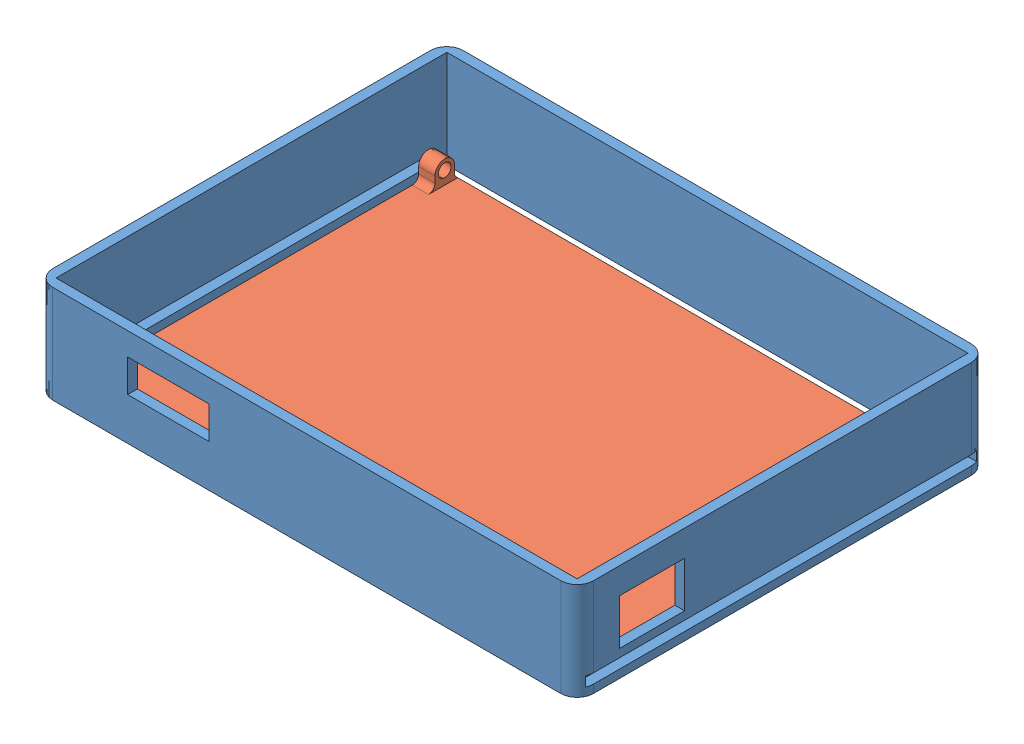
SolidWorks assembly 装配体1, configuration 默认. Lengths in mm.
Overall size (166 32 126).
2 component instances, 2 part files, 2 mates.
Components (placement in the parent):
- 外框-1: 外框 [默认] at (-89.7958 -29.2658 166) size (166 30 126)
- 后盖-1: 后盖 [默认] at (-90.2958 -31.2658 165.6592) size (159 9 116)
Mates (geometry in assembly coordinates):
- 重合1: coincident: plane of assembly; plane of assembly; plane of 外框-1 through (-169.7958 0.7342 106) normal (1 0 0); plane of 后盖-1 through (-169.7958 -29.2658 107.6592) normal (-1 0 0)
- 重合3: coincident: plane of assembly; plane of assembly; plane of 外框-1 through (-89.7958 -29.2658 166) normal (0 -1 0); plane of 后盖-1 through (-90.2958 -29.2658 165.6592) normal (0 1 0)
